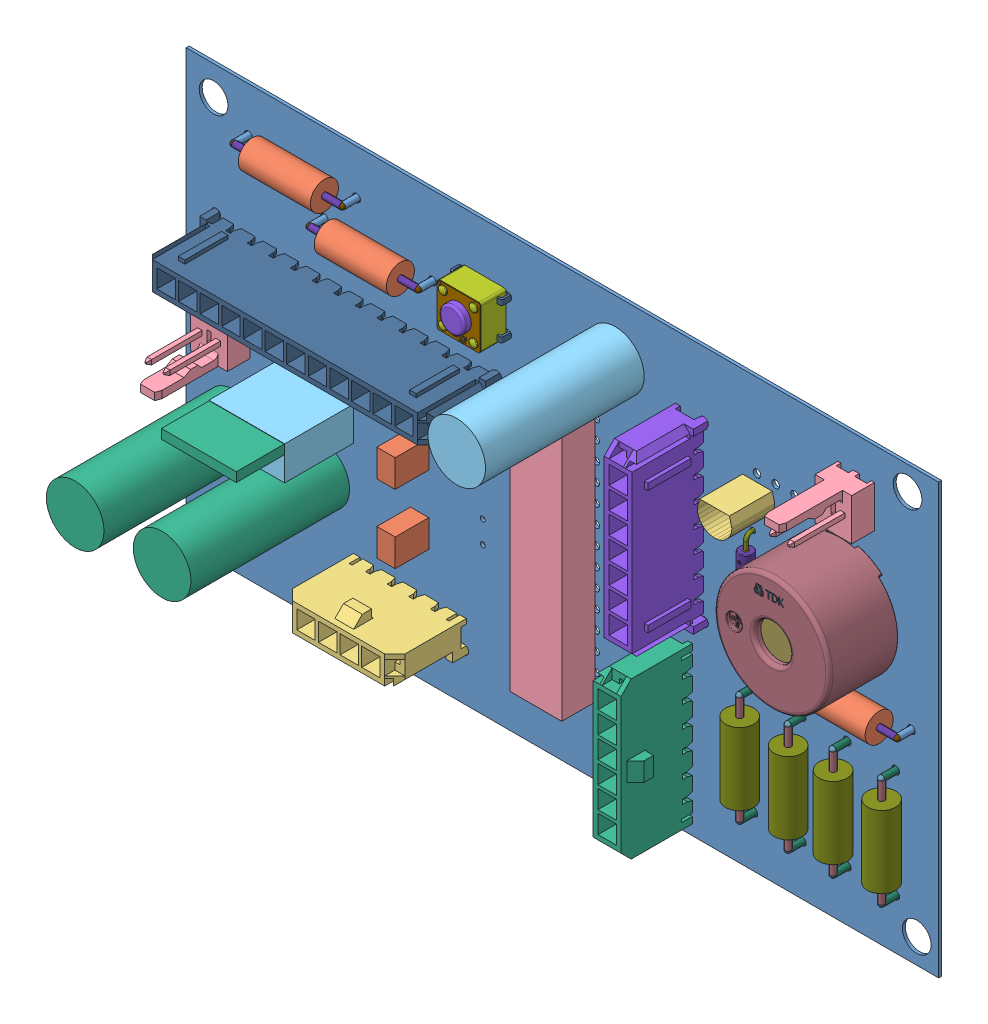
SolidWorks assembly Alarm_Clock, configuration Default. Lengths in mm.
Overall size (104.39 59.56 29).
209 component instances, 45 part files, 0 mates.
Components (placement in the parent):
- Alarm_Clock.step-1: Alarm_Clock.step [Default] at origin size (104.39 59.56 29)
  - Board.step-1: Board.step [Default] at origin size (104.39 59.56 0.41)
    - Open CASCADE STEP translator 6.8 1.1.1.step-1: Open CASCADE STEP translator 6.8 1.1.1.step [Default] at (0 0 -0.4115) size (104.39 59.56 0.41)
  - P6.step-1: P6.step [Default] at origin size (15.65 5.57 13.08)
    - 66200411122.step-1: 66200411122.step [Default] at (71.0674 60.0699 4.98) x (1 0 0) z (0 1 0) size (15.65 13.08 5.57)
      - 6620xx11122_PIN.step-1: 6620xx11122_PIN.step [Default] at (-4.5 1.3806 0.255) x (-1 0 0) z (0 0 -1) size (0.64 10.1 0.9)
      - 6620xx11122_PIN.step-2: 6620xx11122_PIN.step [Default] at (-1.5 1.3806 0.255) size (0.64 10.1 0.9)
      - 6620xx11122_PIN.step-3: 6620xx11122_PIN.step [Default] at (1.5 1.3806 0.255) x (-1 0 0) z (0 0 -1) size (0.64 10.1 0.9)
      - 6620xx11122_PIN.step-4: 6620xx11122_PIN.step [Default] at (4.5 1.3806 0.255) size (0.64 10.1 0.9)
      - 66200411122-0.step-1: 66200411122-0.step [Default] at origin size (15.65 11 5.57)
  - U2.step-1: U2.step [Default] at origin size (7.2 35.3 4.58)
    - 5917139056.step-1: 5917139056.step [Default] at (93.091 78.74 0) size (7.2 35.3 4.58)
      - Extruded.step-1: Extruded.step [Default] at origin size (7.2 35.3 4.58)
  - U1.step-1: U1.step [Default] at origin size (10.5 4.7 16.2)
    - 5917143376.step-1: 5917143376.step [Default] at (61.468 81.322 3.5) size (10.5 4.7 9.55)
      - Extruded-1.step-1: Extruded-1.step [Default] at origin size (10.5 4.7 9.55)
    - 5917143056.step-1: 5917143056.step [Default] at (61.468 82.972 13.05) size (10.4 1.3 6.65)
      - Extruded-2.step-1: Extruded-2.step [Default] at origin size (10.4 1.3 6.65)
  - SW1.step-1: SW1.step [Default] at origin size (7.8 5.99 8.11)
    - Switch_TE_1825910-2_eec.step-1: Switch_TE_1825910-2_eec.step [Default] at (81.407 101.6 0) size (7.8 5.99 8.11)
      - Body.step-1: Body.step [Default] at (0 0 4.3) x (0 -1 0) z (0 0 1) size (5.99 5.99 3.9)
      - button.step-1: button.step [Default] at (0 0 4.3) x (0 -1 0) z (0 0 1) size (3.51 3.51 1.1)
      - cover.step-1: cover.step [Default] at (0 0 4.3) x (0 -1 0) z (0 0 1) size (5.99 5.99 0.1)
      - leads.step-1: leads.step [Default] at (0 0 4.3) x (0 -1 0) z (0 0 1) size (5.21 7.8 4.81)
      - circle.step-1: circle.step [Default] at (-2.6803 2.6863 3.6) size (0.4 0.4 0)
      - TE_Connectivity.step-1: TE_Connectivity.step [Default] at (-0.1925 -2.4218 3.6) size (2.27 0.85 0.01)
  - R9.step-1: R9.step [Default] at origin size (3.9 15.83 5.9)
    - 5917146656.step-1: 5917146656.step [Default] at (131.699 58.921 1.95) x (0 0 -1) z (0 1 0) size (0.83 0.83 15)
      - Cylinder.step-1: Cylinder.step [Default] at origin size (0.83 0.83 15)
    - 5917146416.step-1: 5917146416.step [Default] at (131.6989 73.9211 1.95) x (0 1 0) z (0 0 1) size (0.83 0.83 0.83)
      - Sphere.step-1: Sphere.step [Default] at origin size (0.83 0.83 0.83)
    - 5917146416.step-2: 5917146416.step [Default] at (131.699 58.921 1.95) x (0 1 0) z (0 0 1) size (0.83 0.83 0.83)
      - Sphere.step-1: Sphere.step [Default] at origin size (0.83 0.83 0.83)
    - 5917146016.step-1: 5917146016.step [Default] at (131.6989 73.9211 -2) x (0 1 0) z (0 0 1) size (0.83 0.83 3.95)
      - Cylinder-3.step-1: Cylinder-3.step [Default] at origin size (0.83 0.83 3.95)
    - 5917146016.step-2: 5917146016.step [Default] at (131.699 58.9211 -2) x (0 1 0) z (0 0 1) size (0.83 0.83 3.95)
      - Cylinder-3.step-1: Cylinder-3.step [Default] at origin size (0.83 0.83 3.95)
    - 5917145616.step-1: 5917145616.step [Default] at (131.699 61.4209 1.95) x (0 0 -1) z (0 1 0) size (3.9 3.9 10)
      - Cylinder-4.step-1: Cylinder-4.step [Default] at origin size (3.9 3.9 10)
  - R8.step-1: R8.step [Default] at origin size (3.9 15.83 5.9)
    - 5917145616.step-1: 5917145616.step [Default] at (118.745 61.4209 1.95) x (0 0 -1) z (0 1 0) size (3.9 3.9 10)
      - Cylinder-4.step-1: Cylinder-4.step [Default] at origin size (3.9 3.9 10)
    - 5917146016.step-1: 5917146016.step [Default] at (118.745 58.9211 -2) x (0 1 0) z (0 0 1) size (0.83 0.83 3.95)
      - Cylinder-3.step-1: Cylinder-3.step [Default] at origin size (0.83 0.83 3.95)
    - 5917146016.step-2: 5917146016.step [Default] at (118.7449 73.9211 -2) x (0 1 0) z (0 0 1) size (0.83 0.83 3.95)
      - Cylinder-3.step-1: Cylinder-3.step [Default] at origin size (0.83 0.83 3.95)
    - 5917146416.step-1: 5917146416.step [Default] at (118.745 58.921 1.95) x (0 1 0) z (0 0 1) size (0.83 0.83 0.83)
      - Sphere.step-1: Sphere.step [Default] at origin size (0.83 0.83 0.83)
    - 5917146416.step-2: 5917146416.step [Default] at (118.7449 73.9211 1.95) x (0 1 0) z (0 0 1) size (0.83 0.83 0.83)
      - Sphere.step-1: Sphere.step [Default] at origin size (0.83 0.83 0.83)
    - 5917146656.step-1: 5917146656.step [Default] at (118.745 58.921 1.95) x (0 0 -1) z (0 1 0) size (0.83 0.83 15)
      - Cylinder.step-1: Cylinder.step [Default] at origin size (0.83 0.83 15)
  - R7.step-1: R7.step [Default] at origin size (3.9 15.83 5.9)
    - 5917145616.step-1: 5917145616.step [Default] at (125.476 61.2939 1.95) x (0 0 -1) z (0 1 0) size (3.9 3.9 10)
      - Cylinder-4.step-1: Cylinder-4.step [Default] at origin size (3.9 3.9 10)
    - 5917146016.step-1: 5917146016.step [Default] at (125.476 58.7941 -2) x (0 1 0) z (0 0 1) size (0.83 0.83 3.95)
      - Cylinder-3.step-1: Cylinder-3.step [Default] at origin size (0.83 0.83 3.95)
    - 5917146016.step-2: 5917146016.step [Default] at (125.4759 73.7941 -2) x (0 1 0) z (0 0 1) size (0.83 0.83 3.95)
      - Cylinder-3.step-1: Cylinder-3.step [Default] at origin size (0.83 0.83 3.95)
    - 5917146416.step-1: 5917146416.step [Default] at (125.476 58.794 1.95) x (0 1 0) z (0 0 1) size (0.83 0.83 0.83)
      - Sphere.step-1: Sphere.step [Default] at origin size (0.83 0.83 0.83)
    - 5917146416.step-2: 5917146416.step [Default] at (125.4759 73.7941 1.95) x (0 1 0) z (0 0 1) size (0.83 0.83 0.83)
      - Sphere.step-1: Sphere.step [Default] at origin size (0.83 0.83 0.83)
    - 5917146656.step-1: 5917146656.step [Default] at (125.476 58.794 1.95) x (0 0 -1) z (0 1 0) size (0.83 0.83 15)
      - Cylinder.step-1: Cylinder.step [Default] at origin size (0.83 0.83 15)
  - R6.step-1: R6.step [Default] at origin size (3.9 15.83 5.9)
    - 5917145616.step-1: 5917145616.step [Default] at (138.43 61.3009 1.95) x (0 0 -1) z (0 1 0) size (3.9 3.9 10)
      - Cylinder-4.step-1: Cylinder-4.step [Default] at origin size (3.9 3.9 10)
    - 5917146016.step-1: 5917146016.step [Default] at (138.43 58.8011 -2) x (0 1 0) z (0 0 1) size (0.83 0.83 3.95)
      - Cylinder-3.step-1: Cylinder-3.step [Default] at origin size (0.83 0.83 3.95)
    - 5917146016.step-2: 5917146016.step [Default] at (138.4299 73.8011 -2) x (0 1 0) z (0 0 1) size (0.83 0.83 3.95)
      - Cylinder-3.step-1: Cylinder-3.step [Default] at origin size (0.83 0.83 3.95)
    - 5917146416.step-1: 5917146416.step [Default] at (138.43 58.801 1.95) x (0 1 0) z (0 0 1) size (0.83 0.83 0.83)
      - Sphere.step-1: Sphere.step [Default] at origin size (0.83 0.83 0.83)
    - 5917146416.step-2: 5917146416.step [Default] at (138.4299 73.8011 1.95) x (0 1 0) z (0 0 1) size (0.83 0.83 0.83)
      - Sphere.step-1: Sphere.step [Default] at origin size (0.83 0.83 0.83)
    - 5917146656.step-1: 5917146656.step [Default] at (138.43 58.801 1.95) x (0 0 -1) z (0 1 0) size (0.83 0.83 15)
      - Cylinder.step-1: Cylinder.step [Default] at origin size (0.83 0.83 15)
  - R5.step-1: R5.step [Default] at origin size (15.83 3.9 5.9)
    - 5919244592.step-1: 5919244592.step [Default] at (63.634 105.156 1.95) x (0 0 -1) z (-1 0 0) size (0.83 0.83 15)
      - Cylinder-5.step-1: Cylinder-5.step [Default] at origin size (0.83 0.83 15)
    - 5919245152.step-1: 5919245152.step [Default] at (48.6339 105.1559 1.95) x (-1 0 0) z (0 0 1) size (0.83 0.83 0.83)
      - Sphere-6.step-1: Sphere-6.step [Default] at origin size (0.83 0.83 0.83)
    - 5919245152.step-2: 5919245152.step [Default] at (63.634 105.156 1.95) x (-1 0 0) z (0 0 1) size (0.83 0.83 0.83)
      - Sphere-6.step-1: Sphere-6.step [Default] at origin size (0.83 0.83 0.83)
    - 5919245872.step-1: 5919245872.step [Default] at (48.6339 105.1559 -2) x (-1 0 0) z (0 0 1) size (0.83 0.83 3.95)
      - Cylinder-7.step-1: Cylinder-7.step [Default] at origin size (0.83 0.83 3.95)
    - 5919245872.step-2: 5919245872.step [Default] at (63.6339 105.156 -2) x (-1 0 0) z (0 0 1) size (0.83 0.83 3.95)
      - Cylinder-7.step-1: Cylinder-7.step [Default] at origin size (0.83 0.83 3.95)
    - 5919246432.step-1: 5919246432.step [Default] at (61.1341 105.156 1.95) x (0 0 -1) z (-1 0 0) size (3.9 3.9 10)
      - Cylinder-8.step-1: Cylinder-8.step [Default] at origin size (3.9 3.9 10)
  - R4.step-1: R4.step [Default] at origin size (15.83 3.9 5.9)
    - 5919246432.step-1: 5919246432.step [Default] at (138.0961 79.756 1.95) x (0 0 -1) z (-1 0 0) size (3.9 3.9 10)
      - Cylinder-8.step-1: Cylinder-8.step [Default] at origin size (3.9 3.9 10)
    - 5919245872.step-1: 5919245872.step [Default] at (140.5959 79.756 -2) x (-1 0 0) z (0 0 1) size (0.83 0.83 3.95)
      - Cylinder-7.step-1: Cylinder-7.step [Default] at origin size (0.83 0.83 3.95)
    - 5919245872.step-2: 5919245872.step [Default] at (125.5959 79.7559 -2) x (-1 0 0) z (0 0 1) size (0.83 0.83 3.95)
      - Cylinder-7.step-1: Cylinder-7.step [Default] at origin size (0.83 0.83 3.95)
    - 5919245152.step-1: 5919245152.step [Default] at (140.5959 79.756 1.95) x (-1 0 0) z (0 0 1) size (0.83 0.83 0.83)
      - Sphere-6.step-1: Sphere-6.step [Default] at origin size (0.83 0.83 0.83)
    - 5919245152.step-2: 5919245152.step [Default] at (125.5959 79.7559 1.95) x (-1 0 0) z (0 0 1) size (0.83 0.83 0.83)
      - Sphere-6.step-1: Sphere-6.step [Default] at origin size (0.83 0.83 0.83)
    - 5919244592.step-1: 5919244592.step [Default] at (140.596 79.756 1.95) x (0 0 -1) z (-1 0 0) size (0.83 0.83 15)
      - Cylinder-5.step-1: Cylinder-5.step [Default] at origin size (0.83 0.83 15)
  - R1.step-1: R1.step [Default] at origin size (15.83 3.9 5.9)
    - 5919244592.step-1: 5919244592.step [Default] at (74.168 100.457 1.95) x (0 0 -1) z (-1 0 0) size (0.83 0.83 15)
      - Cylinder-5.step-1: Cylinder-5.step [Default] at origin size (0.83 0.83 15)
    - 5919245152.step-1: 5919245152.step [Default] at (59.1679 100.4569 1.95) x (-1 0 0) z (0 0 1) size (0.83 0.83 0.83)
      - Sphere-6.step-1: Sphere-6.step [Default] at origin size (0.83 0.83 0.83)
    - 5919245152.step-2: 5919245152.step [Default] at (74.168 100.457 1.95) x (-1 0 0) z (0 0 1) size (0.83 0.83 0.83)
      - Sphere-6.step-1: Sphere-6.step [Default] at origin size (0.83 0.83 0.83)
    - 5919245872.step-1: 5919245872.step [Default] at (59.1679 100.4569 -2) x (-1 0 0) z (0 0 1) size (0.83 0.83 3.95)
      - Cylinder-7.step-1: Cylinder-7.step [Default] at origin size (0.83 0.83 3.95)
    - 5919245872.step-2: 5919245872.step [Default] at (74.1679 100.457 -2) x (-1 0 0) z (0 0 1) size (0.83 0.83 3.95)
      - Cylinder-7.step-1: Cylinder-7.step [Default] at origin size (0.83 0.83 3.95)
    - 5919246432.step-1: 5919246432.step [Default] at (71.6681 100.457 1.95) x (0 0 -1) z (-1 0 0) size (3.9 3.9 10)
      - Cylinder-8.step-1: Cylinder-8.step [Default] at origin size (3.9 3.9 10)
  - Q1.step-1: Q1.step [Default] at origin size (4.79 3.67 5.95)
    - 5917134816.step-1: 5917134816.step [Default] at (121.793 99.457 2.54) size (4.79 3.67 5.95)
      - Extruded-9.step-1: Extruded-9.step [Default] at origin size (4.79 3.67 5.95)
  - P5.step-1: P5.step [Default] at origin size (5.08 5.8 15.26)
    - 022272021.step-1: 022272021.step [Default] at (132.9691 104.0131 1.6) x (1 0 0) z (0 -1 0) size (5.08 15.26 5.8)
      - Open CASCADE STEP translator 6.8 1.14.1.1.step-1: Open CASCADE STEP translator 6.8 1.14.1.1.step [Default] at origin size (5.08 15.26 5.8)
      - Open CASCADE STEP translator 6.8 1.14.1.2.step-1: Open CASCADE STEP translator 6.8 1.14.1.2.step [Default] at origin
  - P4.step-1: P4.step [Default] at origin size (5.57 21.65 13.75)
    - 66200611122.step-1: 66200611122.step [Default] at (108.0759 64.1086 4.98) x (0 -1 0) z (1 0 0) size (21.65 13.75 5.57)
      - 6620xx11122_PIN-10.step-1: 6620xx11122_PIN-10.step [Default] at (-7.5 1.3806 0.255) x (-1 0 0) z (0 0 -1) size (0.64 10.1 0.9)
      - 6620xx11122_PIN-10.step-2: 6620xx11122_PIN-10.step [Default] at (-4.5 1.3806 0.255) size (0.64 10.1 0.9)
      - 6620xx11122_PIN-10.step-3: 6620xx11122_PIN-10.step [Default] at (-1.5 2.0477 0.25) x (-1 0 0) z (0 0 -1) size (0.64 10.1 0.9)
      - 6620xx11122_PIN-10.step-4: 6620xx11122_PIN-10.step [Default] at (1.5 2.0477 0.25) size (0.64 10.1 0.9)
      - 6620xx11122_PIN-10.step-5: 6620xx11122_PIN-10.step [Default] at (4.5 2.0477 0.25) x (-1 0 0) z (0 0 -1) size (0.64 10.1 0.9)
      - 6620xx11122_PIN-10.step-6: 6620xx11122_PIN-10.step [Default] at (7.5 2.0477 0.25) size (0.64 10.1 0.9)
      - 66200611122-11.step-1: 66200611122-11.step [Default] at origin size (21.65 11 5.57)
  - P3.step-1: P3.step [Default] at origin size (5.57 24.65 13.75)
    - 66200711122.step-1: 66200711122.step [Default] at (110.1101 90.3304 4.98) x (0 1 0) z (-1 0 0) size (24.65 13.75 5.57)
      - 6620xx11122_PIN-12.step-1: 6620xx11122_PIN-12.step [Default] at (-9 1.3806 0.255) x (-1 0 0) z (0 0 -1) size (0.64 10.1 0.9)
      - 6620xx11122_PIN-12.step-2: 6620xx11122_PIN-12.step [Default] at (-6 1.3806 0.255) size (0.64 10.1 0.9)
      - 6620xx11122_PIN-12.step-3: 6620xx11122_PIN-12.step [Default] at (-3 2.0477 0.25) x (-1 0 0) z (0 0 -1) size (0.64 10.1 0.9)
      - 6620xx11122_PIN-12.step-4: 6620xx11122_PIN-12.step [Default] at (0 2.0477 0.25) size (0.64 10.1 0.9)
      - 6620xx11122_PIN-12.step-5: 6620xx11122_PIN-12.step [Default] at (3 2.0477 0.25) x (-1 0 0) z (0 0 -1) size (0.64 10.1 0.9)
      - 6620xx11122_PIN-12.step-6: 6620xx11122_PIN-12.step [Default] at (6 2.0477 0.25) size (0.64 10.1 0.9)
      - 6620xx11122_PIN-12.step-7: 6620xx11122_PIN-12.step [Default] at (9 2.0477 0.25) x (-1 0 0) z (0 0 -1) size (0.64 10.1 0.9)
      - 66200711122-13.step-1: 66200711122-13.step [Default] at origin size (24.65 11 5.57)
  - P2.step-1: P2.step [Default] at origin size (39.65 5.57 13.08)
    - 66201211122.step-1: 66201211122.step [Default] at (63.6486 91.8221 4.98) x (-1 0 0) z (0 -1 0) size (39.65 13.08 5.57)
      - 6620xx11122_PIN-14.step-1: 6620xx11122_PIN-14.step [Default] at (-16.5 1.3806 0.255) x (-1 0 0) z (0 0 -1) size (0.64 10.1 0.9)
      - 6620xx11122_PIN-14.step-2: 6620xx11122_PIN-14.step [Default] at (-13.5 1.3806 0.255) size (0.64 10.1 0.9)
      - 6620xx11122_PIN-14.step-3: 6620xx11122_PIN-14.step [Default] at (-10.5 1.3806 0.255) x (-1 0 0) z (0 0 -1) size (0.64 10.1 0.9)
      - 6620xx11122_PIN-14.step-4: 6620xx11122_PIN-14.step [Default] at (-4.5 1.3806 0.255) x (-1 0 0) z (0 0 -1) size (0.64 10.1 0.9)
      - 6620xx11122_PIN-14.step-5: 6620xx11122_PIN-14.step [Default] at (1.5 1.3806 0.255) x (-1 0 0) z (0 0 -1) size (0.64 10.1 0.9)
      - 6620xx11122_PIN-14.step-6: 6620xx11122_PIN-14.step [Default] at (7.5 1.3806 0.255) x (-1 0 0) z (0 0 -1) size (0.64 10.1 0.9)
      - 6620xx11122_PIN-14.step-7: 6620xx11122_PIN-14.step [Default] at (13.5 1.3806 0.255) x (-1 0 0) z (0 0 -1) size (0.64 10.1 0.9)
      - 6620xx11122_PIN-14.step-8: 6620xx11122_PIN-14.step [Default] at (-7.5 1.3806 0.255) size (0.64 10.1 0.9)
      - 6620xx11122_PIN-14.step-9: 6620xx11122_PIN-14.step [Default] at (-1.5 1.3806 0.255) size (0.64 10.1 0.9)
      - 6620xx11122_PIN-14.step-10: 6620xx11122_PIN-14.step [Default] at (4.5 1.3806 0.255) size (0.64 10.1 0.9)
      - 6620xx11122_PIN-14.step-11: 6620xx11122_PIN-14.step [Default] at (10.5 1.3806 0.255) size (0.64 10.1 0.9)
      - 6620xx11122_PIN-14.step-12: 6620xx11122_PIN-14.step [Default] at (16.5 1.3806 0.255) size (0.64 10.1 0.9)
      - 66201211122-15.step-1: 66201211122-15.step [Default] at origin size (39.65 11 5.57)
  - P1.step-1: P1.step [Default] at origin size (5.08 5.8 15.26)
    - 022272021.step-1: 022272021.step [Default] at (46.3549 81.4069 1.6) x (-1 0 0) z (0 1 0) size (5.08 15.26 5.8)
      - Open CASCADE STEP translator 6.8 1.14.1.1.step-1: Open CASCADE STEP translator 6.8 1.14.1.1.step [Default] at origin size (5.08 15.26 5.8)
      - Open CASCADE STEP translator 6.8 1.14.1.2.step-1: Open CASCADE STEP translator 6.8 1.14.1.2.step [Default] at origin
  - LS1.step-1: LS1.step [Default] at origin size (16 16 13.9)
    - Speak_TDK_SDC1610M5-01_eec.step-1: Speak_TDK_SDC1610M5-01_eec.step [Default] at (131.231 90.424 0) size (16 16 13.9)
      - 1.step-1: 1.step [Default] at origin size (5.8 0.8 4.4)
      - 2.step-1: 2.step [Default] at origin size (5 5 0.5)
      - 3.step-1: 3.step [Default] at origin size (16 16 10)
      - TDK_Logo.step-1: TDK_Logo.step [Default] at (0.0013 6.3762 9.999) size (4.12 1.23 0)
  - D1.step-1: D1.step [Default] at origin size (1.91 8.12 5.91)
    - Diode_ON_Semiconductor_1N914B_eec.step-1: Diode_ON_Semiconductor_1N914B_eec.step [Default] at (118.618 88.9 0) x (0 1 0) z (0 0 1) size (8.12 1.91 5.91)
      - 1-16.step-1: 1-16.step [Default] at (0 -0.955 0.955) size (0.88 1.91 1.91)
      - 2-17.step-1: 2-17.step [Default] at (0 -0.955 0.955) size (8.12 0.7 5.3)
      - 3-18.step-1: 3-18.step [Default] at (0 -0.955 0.955) size (3.8 1.91 1.91)
      - 4.step-1: 4.step [Default] at (0 -0.955 0.955) size (0.45 0.45 0.96)
  - C5.step-1: C5.step [Default] at origin size (2.54 3.81 11.66)
    - 5917146896.step-1: 5917146896.step [Default] at (72.3899 68.5801 -7) size (0.51 0.51 7)
      - Extruded-19.step-1: Extruded-19.step [Default] at origin size (0.51 0.51 7)
    - 5917146896.step-2: 5917146896.step [Default] at (72.39 71.1201 -7) size (0.51 0.51 7)
      - Extruded-19.step-1: Extruded-19.step [Default] at origin size (0.51 0.51 7)
    - 5917140256.step-1: 5917140256.step [Default] at (72.39 69.85 0) size (2.54 3.81 4.66)
      - Extruded-20.step-1: Extruded-20.step [Default] at origin size (2.54 3.81 4.66)
  - C4.step-1: C4.step [Default] at origin size (2.54 3.81 11.66)
    - 5917146896.step-1: 5917146896.step [Default] at (72.3899 78.1051 -7) size (0.51 0.51 7)
      - Extruded-19.step-1: Extruded-19.step [Default] at origin size (0.51 0.51 7)
    - 5917146896.step-2: 5917146896.step [Default] at (72.39 80.6451 -7) size (0.51 0.51 7)
      - Extruded-19.step-1: Extruded-19.step [Default] at origin size (0.51 0.51 7)
    - 5917140256.step-1: 5917140256.step [Default] at (72.39 79.375 0) size (2.54 3.81 4.66)
      - Extruded-20.step-1: Extruded-20.step [Default] at origin size (2.54 3.81 4.66)
  - C3.step-1: C3.step [Default] at origin size (8 8 25)
    - 5917142176.step-1: 5917142176.step [Default] at (97.7901 103.6321 -3) size (0.6 0.6 3)
      - Cylinder-21.step-1: Cylinder-21.step [Default] at origin size (0.6 0.6 3)
    - 5917141696.step-1: 5917141696.step [Default] at (101.29 103.6321 -2) size (0.6 0.6 2)
      - Cylinder-22.step-1: Cylinder-22.step [Default] at origin size (0.6 0.6 2)
    - 5917141296.step-1: 5917141296.step [Default] at (99.5401 103.6321 0) size (8 8 22)
      - Cylinder-23.step-1: Cylinder-23.step [Default] at origin size (8 8 22)
  - C2.step-1: C2.step [Default] at origin size (8 8 25)
    - 5917141056.step-1: 5917141056.step [Default] at (58.6741 69.6239 0) x (0 -1 0) z (0 0 1) size (8 8 22)
      - Cylinder-24.step-1: Cylinder-24.step [Default] at origin size (8 8 22)
    - 5917140816.step-1: 5917140816.step [Default] at (58.6741 67.874 -2) x (0 -1 0) z (0 0 1) size (0.6 0.6 2)
      - Cylinder-25.step-1: Cylinder-25.step [Default] at origin size (0.6 0.6 2)
    - 5917140576.step-1: 5917140576.step [Default] at (58.6741 71.3739 -3) x (0 -1 0) z (0 0 1) size (0.6 0.6 3)
      - Cylinder-26.step-1: Cylinder-26.step [Default] at origin size (0.6 0.6 3)
  - C1.step-1: C1.step [Default] at origin size (8 8 25)
    - 5917141056.step-1: 5917141056.step [Default] at (46.6091 69.6239 0) x (0 -1 0) z (0 0 1) size (8 8 22)
      - Cylinder-24.step-1: Cylinder-24.step [Default] at origin size (8 8 22)
    - 5917140816.step-1: 5917140816.step [Default] at (46.6091 67.874 -2) x (0 -1 0) z (0 0 1) size (0.6 0.6 2)
      - Cylinder-25.step-1: Cylinder-25.step [Default] at origin size (0.6 0.6 2)
    - 5917140576.step-1: 5917140576.step [Default] at (46.6091 71.3739 -3) x (0 -1 0) z (0 0 1) size (0.6 0.6 3)
      - Cylinder-26.step-1: Cylinder-26.step [Default] at origin size (0.6 0.6 3)
